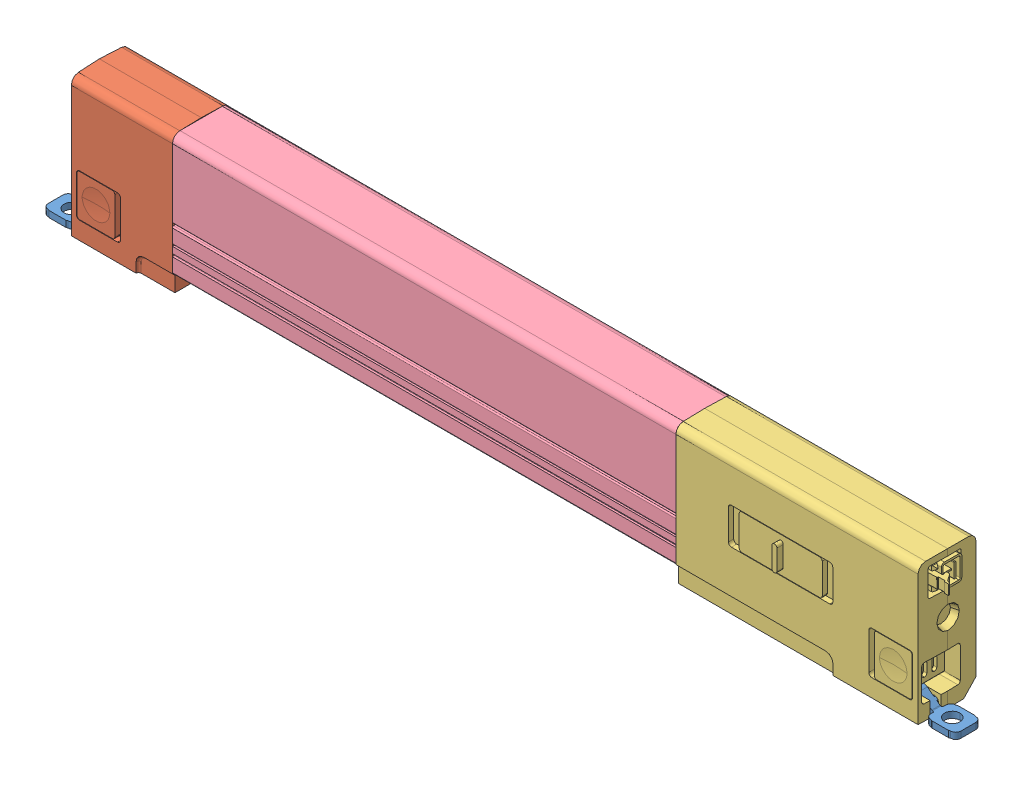
SolidWorks assembly 7859_000, configuration Default. Lengths in mm.
Overall size (362.8 57.47 25.5).
5 component instances, 4 part files, 15 mates.
Components (placement in the parent):
- 7859_000-clamp-1: 7859_000-clamp [Default] at (-347.3001 -51.7777 -9.5) size (25.74 7.09 10.4)
- 7859_000-side1-1: 7859_000-side1 [Default] at (-309.4001 -54.7777 -2.5) size (40.5 57.47 23)
- 7859_000-clamp-2: 7859_000-clamp [Default] at (-15.5041 -51.7777 -9.29) x (-1 0 0) z (0 0 -1) size (25.74 7.09 10.4)
- 7859_000-side2-1: 7859_000-side2 [Default] at (-109.4001 -54.7777 -2.5) size (102.65 57.47 25.5)
- 7859_000-middel-1: 7859_000-middel [Default] at (-209.4001 -54.76 -2.45) size (200 47.76 22.9)
Mates (geometry in assembly coordinates):
- Deckungsgleich1: coincident aligned: plane of 7859_000-side2-1 through (-12.7001 63.6954 -2.5) normal (0 0 1); plane of 7859_000-middel-1 through (-18.7553 18.0348 8.3691) normal (0 0 1)
- Konzentrisch1: concentric aligned: cylinder of 7859_000-side2-1 through (-12.7001 63.6954 -5.5) axis (-1 0 0) radius 3; cylinder of 7859_000-middel-1 through (-18.7553 18.0348 5.3691) axis (-1 0 0) radius 3
- Deckungsgleich2: coincident anti-aligned: plane of 7859_000-side2-1 through (-109.4001 63.6954 -5.5) normal (-1 0 0); plane of 7859_000-middel-1 through (-18.7553 -26.2252 7.9191) normal (1 0 0)
- Deckungsgleich3: coincident anti-aligned: plane of 7859_000-side1-1 through (-309.4001 63.6954 -5.5) normal (1 0 0); plane of 7859_000-middel-1 through (-218.7553 -26.2252 7.9191) normal (-1 0 0)
- Konzentrisch2: concentric anti-aligned: cylinder of 7859_000-side1-1 through (-350.1501 63.6954 -5.5) axis (1 0 0) radius 3; cylinder of 7859_000-middel-1 through (-18.7553 18.0348 5.3691) axis (-1 0 0) radius 3
- Deckungsgleich4: coincident aligned: plane of 7859_000-side1-1 through (-350.1501 63.6954 -2.5) normal (0 0 1); plane of 7859_000-middel-1 through (-18.7553 18.0348 8.3691) normal (0 0 1)
- Konzentrisch3: concentric anti-aligned: cylinder of 7859_000-clamp-2 through (-15.5041 14.9177 -13.69) axis (0 0 1) radius 1.4; cylinder of 7859_000-side2-1 through (-15.5041 14.9177 -4.9) axis (0 0 -1) radius 1.5
- Deckungsgleich5: coincident aligned: plane of 7859_000-clamp-2 through (0 11.9177 -10.94) normal (0 -1 0); plane of 7859_000-side2-1 through (-12.7001 11.9177 -2.5) normal (0 -1 0)
- Breite1: width anti-aligned: plane of 7859_000-clamp-2 through (-12.5962 14.9177 -7.64) normal (0 0 1); plane of 7859_000-clamp-2 through (-12.5962 14.9177 -10.94) normal (0 0 -1); plane of 7859_000-side2-1 through (-28.7001 18.9177 -7.19) normal (0 0 -1); plane of 7859_000-side2-1 through (-11.9501 18.9177 -11.39) normal (0 0 1)
- Konzentrisch4: concentric aligned: cylinder of 7859_000-clamp-1 through (-347.3001 14.9177 -5.1) axis (0 0 -1) radius 1.4; cylinder of 7859_000-side1-1 through (-347.3001 14.9177 -4.9) axis (0 0 -1) radius 1.5
- Deckungsgleich6: coincident aligned: plane of 7859_000-clamp-1 through (-362.8042 11.9177 -7.85) normal (0 -1 0); plane of 7859_000-side1-1 through (-350.1501 11.9177 -2.5) normal (0 -1 0)
- Breite2: width aligned: plane of 7859_000-clamp-1 through (-350.208 14.9177 -7.85) normal (0 0 1); plane of 7859_000-clamp-1 through (-350.208 14.9177 -11.15) normal (0 0 -1); plane of 7859_000-side1-1 through (-335.1201 17.9877 -11.4) normal (0 0 1); plane of 7859_000-side1-1 through (-350.1501 17.9877 -7.6) normal (0 0 -1)
- Deckungsgleich7: coincident aligned: plane of 7859_000-side2-1 through (-67.7501 -19.5777 0) normal (0 0 1); plane of assembly
- Deckungsgleich8: coincident aligned: plane of 7859_000-clamp-2 through (0 -52.2777 -10.94) normal (1 0 0); plane of assembly
- Deckungsgleich9: coincident aligned: plane of 7859_000-middel-1 through (-109.4001 0 -22.3) normal (0 1 0); plane of assembly
